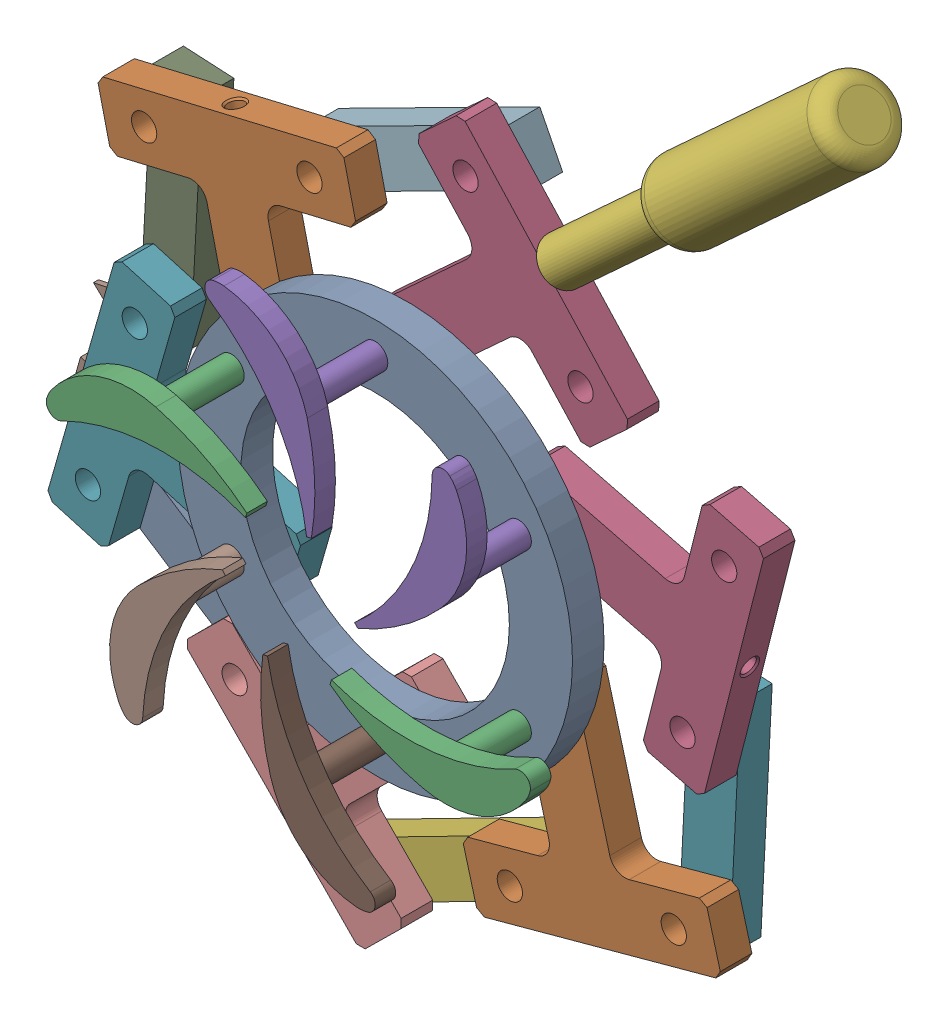
SolidWorks assembly GV000, configuration Default. Lengths in mm.
Overall size (274.13 316.38 61.3).
26 component instances, 6 part files, 21 mates.
Components (placement in the parent):
- GV006-1: GV006 [Default] at origin size (125 125 10)
- GV Sub Assembly-1: GV Sub Assembly [Default] at (-45.4663 26.25 -10) x (0.973153 0.23016 0) z (0 0 1) size (80 78.32 47.3)
  - GV001-1: GV001 [Default] at origin size (80 70 10)
  - GV005-1: GV005 [Default] at (0 0 35.8) size (62.16 25.89 47.3)
- GV Sub Assembly-2: GV Sub Assembly [Default] at (0 52.5 -10) x (0.676513 -0.736431 0) z (0 0 1) size (80 78.32 47.3)
  - GV001-1: GV001 [Default] at origin size (80 70 10)
  - GV005-1: GV005 [Default] at (0 0 35.8) size (62.16 25.89 47.3)
- GV002-1: GV002 [Default] at (81.0074 126.9164 -10) x (0.736431 0.676513 0) z (0.368852 -0.40152 -0.83829) size (142 24 24)
- GV Sub Assembly-3: GV Sub Assembly [Default] at (-45.4663 -26.25 -10) x (0.275768 0.961224 0) z (0 0 1) size (80 78.32 47.3)
  - GV001-1: GV001 [Default] at origin size (80 70 10)
  - GV005-1: GV005 [Default] at (0 0 35.8) size (62.16 25.89 47.3)
- GV003-3: GV003 [Default] at (-84.6308 41.0558 -20) x (0.998574 -0.05338 0) z (0 0 1) size (16 71.4 10)
- GV Sub Assembly-4: GV Sub Assembly [Default] at (0 -52.5 -10) x (-0.702571 0.711613 0) z (0 0 1) size (80 78.32 47.3)
  - GV001-1: GV001 [Default] at origin size (80 70 10)
  - GV005-1: GV005 [Default] at (0 0 35.8) size (62.16 25.89 47.3)
- GV003-4: GV003 [Default] at (-6.0866 93.6173 -20) x (0.451926 -0.892056 0) z (0 0 1) size (16 71.4 10)
- GV003-5: GV003 [Default] at (-77.7128 -53.4024 -20) x (0.544541 0.838734 0) z (0 0 1) size (16 71.4 10)
- GV Sub Assembly-5: GV Sub Assembly [Default] at (45.4663 -26.25 -10) x (-0.964857 -0.262776 0) z (0 0 1) size (80 78.32 47.3)
  - GV001-1: GV001 [Default] at origin size (80 70 10)
  - GV005-1: GV005 [Default] at (0 0 35.8) size (62.16 25.89 47.3)
- GV Sub Assembly-8: GV Sub Assembly [Default] at (45.4663 26.25 -10) x (-0.245319 -0.969442 0) z (0 0 1) size (80 78.32 47.3)
  - GV001-1: GV001 [Default] at origin size (80 70 10)
  - GV005-1: GV005 [Default] at (0 0 35.8) size (62.16 25.89 47.3)
- GV003-8: GV003 [Default] at (7.9845 -94.1662 -20) x (-0.455044 0.890469 0) z (0 0 1) size (16 71.4 10)
- GV003-9: GV003 [Default] at (85.9496 -39.7591 -20) x (0.998741 -0.050173 0) z (0 0 1) size (16 71.4 10)
- GV004-1: GV004 [Default] at (-103.1398 -9.7039 -10) x (0.275768 0.961224 0) z (-0.961224 0.275768 0) size (10 24 20.8)
Mates (geometry in assembly coordinates):
- Hinge1: hinge anti-aligned: plane of GV Sub Assembly-2/GV001-1; circle of GV Sub Assembly-2/GV001-1; plane of GV006-1 through (0 52.5 -5) normal (0 0 1); plane of GV006-1 through (0 0 -5) normal (0 0 -1)
- Hinge2: hinge anti-aligned: circle of GV Sub Assembly-1/GV001-1; circle of GV Sub Assembly-1/GV001-1; plane of GV006-1 through (-45.4663 26.25 -5) normal (0 0 1); plane of GV006-1 through (0 0 -5) normal (0 0 -1)
- Concentric1: concentric aligned: line of GV Sub Assembly-2/GV001-1 through (-2.666 112.4407 -10) axis (-0.044434 0.999012 0); line of GV002-1 through (-2.155 100.9521 -10) axis (-0.044434 0.999012 0)
- Hinge7: hinge anti-aligned: cylinder of GV Sub Assembly-3/GV001-1 through (-45.4663 -26.25 -15) axis (0 0 1) radius 4; cylinder of GV Sub Assembly-3/GV001-1 through (-45.4663 -26.25 -5) axis (0 0 1) radius 4; plane of GV006-1 through (-45.4663 -26.25 -5) normal (0 0 1); plane of GV006-1 through (0 0 -5) normal (0 0 -1)
- Hinge8: hinge anti-aligned: cylinder of GV003-3 through (-102.2423 25.9364 -25) axis (0 0 1) radius 4; cylinder of GV Sub Assembly-1/GV001-1 through (-102.2423 25.9364 -15) axis (0 0 1) radius 4; plane of GV Sub Assembly-1/GV001-1 through (-45.4663 26.25 -15) normal (0 0 -1); plane of GV003-3 through (-102.1972 -1.7636 -15) normal (0 0 1)
- Hinge9: hinge anti-aligned: cylinder of GV003-3 through (-102.1522 -29.4636 -25) axis (0 0 1) radius 4; cylinder of GV003-3 through (-102.1522 -29.4636 -15) axis (0 0 1) radius 4; plane of GV Sub Assembly-3/GV001-1 through (-102.1972 -1.7636 -15) normal (0 0 1); plane of GV Sub Assembly-3/GV001-1 through (-45.4663 -26.25 -15) normal (0 0 -1)
- Hinge10: hinge anti-aligned: cylinder of GV003-4 through (-29.0951 101.2553 -25) axis (0 0 1) radius 4; cylinder of GV003-4 through (-29.0951 101.2553 -15) axis (0 0 1) radius 4; plane of GV Sub Assembly-2/GV001-1 through (-53.055 87.3551 -15) normal (0 0 1); plane of GV Sub Assembly-2/GV001-1 through (0 52.5 -15) normal (0 0 -1)
- Hinge12: hinge anti-aligned: cylinder of GV003-4 through (-77.0148 73.4549 -25) axis (0 0 1) radius 4; cylinder of GV003-4 through (-77.0148 73.4549 -15) axis (0 0 1) radius 4; plane of GV Sub Assembly-1/GV001-1 through (-53.055 87.3551 -15) normal (0 0 1); plane of GV Sub Assembly-1/GV001-1 through (-45.4663 26.25 -15) normal (0 0 -1)
- Hinge13: hinge anti-aligned: cylinder of GV Sub Assembly-4/GV001-1 through (0 -52.5 -15) axis (0 0 1) radius 4; cylinder of GV Sub Assembly-4/GV001-1 through (0 -52.5 -5) axis (0 0 1) radius 4; plane of GV006-1 through (0 -52.5 -5) normal (0 0 1); plane of GV006-1 through (0 0 -5) normal (0 0 -1)
- Hinge14: hinge anti-aligned: cylinder of GV003-5 through (-74.0218 -75.3234 -25) axis (0 0 1) radius 4; cylinder of GV003-5 through (-74.0218 -75.3234 -15) axis (0 0 1) radius 4; plane of GV Sub Assembly-3/GV001-1 through (-50.0168 -89.1456 -15) normal (0 0 1); plane of GV Sub Assembly-3/GV001-1 through (-45.4663 -26.25 -15) normal (0 0 -1)
- Hinge15: hinge anti-aligned: cylinder of GV003-5 through (-26.0119 -102.9677 -25) axis (0 0 1) radius 4; cylinder of GV Sub Assembly-4/GV001-1 through (-26.0119 -102.9677 -15) axis (0 0 1) radius 4; plane of GV Sub Assembly-4/GV001-1 through (0 -52.5 -15) normal (0 0 -1); plane of GV003-5 through (-50.0168 -89.1456 -15) normal (0 0 1)
- Hinge17: hinge anti-aligned: cylinder of GV Sub Assembly-5/GV001-1 through (45.4663 -26.25 -15) axis (0 0 1) radius 4; cylinder of GV Sub Assembly-5/GV001-1 through (45.4663 -26.25 -5) axis (0 0 1) radius 4; plane of GV006-1 through (45.4663 -26.25 -5) normal (0 0 1); plane of GV006-1 through (0 0 -5) normal (0 0 -1)
- Hinge18: hinge anti-aligned: cylinder of GV003-8 through (27.7797 -102.0166 -25) axis (0 0 1) radius 4; cylinder of GV003-8 through (27.7797 -102.0166 -15) axis (0 0 1) radius 4; plane of GV Sub Assembly-4/GV001-1 through (51.759 -88.1501 -15) normal (0 0 1); plane of GV Sub Assembly-4/GV001-1 through (0 -52.5 -15) normal (0 0 -1)
- Hinge19: hinge anti-aligned: cylinder of GV003-8 through (75.7384 -74.2835 -25) axis (0 0 1) radius 4; cylinder of GV Sub Assembly-5/GV001-1 through (75.7384 -74.2835 -15) axis (0 0 1) radius 4; plane of GV Sub Assembly-5/GV001-1 through (45.4663 -26.25 -15) normal (0 0 -1); plane of GV003-8 through (51.759 -88.1501 -15) normal (0 0 1)
- Hinge20: hinge anti-aligned: cylinder of GV Sub Assembly-8/GV001-1 through (45.4663 26.25 -15) axis (0 0 1) radius 4; cylinder of GV Sub Assembly-8/GV001-1 through (45.4663 26.25 -5) axis (0 0 1) radius 4; plane of GV006-1 through (45.4663 26.25 -5) normal (0 0 1); plane of GV006-1 through (0 0 -5) normal (0 0 -1)
- Hinge21: hinge anti-aligned: cylinder of GV003-9 through (102.218 27.9419 -25) axis (0 0 1) radius 4; cylinder of GV003-9 through (102.218 27.9419 -15) axis (0 0 1) radius 4; plane of GV Sub Assembly-8/GV001-1 through (102.2241 0.2419 -15) normal (0 0 1); plane of GV Sub Assembly-8/GV001-1 through (45.4663 26.25 -15) normal (0 0 -1)
- Hinge22: hinge anti-aligned: cylinder of GV003-9 through (102.2303 -27.4581 -25) axis (0 0 1) radius 4; cylinder of GV003-9 through (102.2303 -27.4581 -15) axis (0 0 1) radius 4; plane of GV Sub Assembly-5/GV001-1 through (102.2241 0.2419 -15) normal (0 0 1); plane of GV Sub Assembly-5/GV001-1 through (45.4663 -26.25 -15) normal (0 0 -1)
- Coincident1: coincident anti-aligned: plane of GV Sub Assembly-2/GV001-1; plane of GV002-1
- Concentric2: concentric aligned: cylinder of GV Sub Assembly-3/GV001-1 through (-96.6111 -57.6222 -10) axis (-0.852413 -0.52287 0) radius 2.5; cylinder of GV004-1 through (-95.2472 -56.7856 -10) axis (-0.852413 -0.52287 0) radius 3.5
- Coincident4: coincident anti-aligned: plane of GV Sub Assembly-3/GV001-1; plane of GV004-1
- Coincident5: coincident anti-aligned: plane of GV Sub Assembly-3/GV001-1 through (-45.4663 -26.25 -15) normal (0 0 -1); plane of GV004-1 through (-97.8616 -52.5235 -15) normal (0 0 1)
